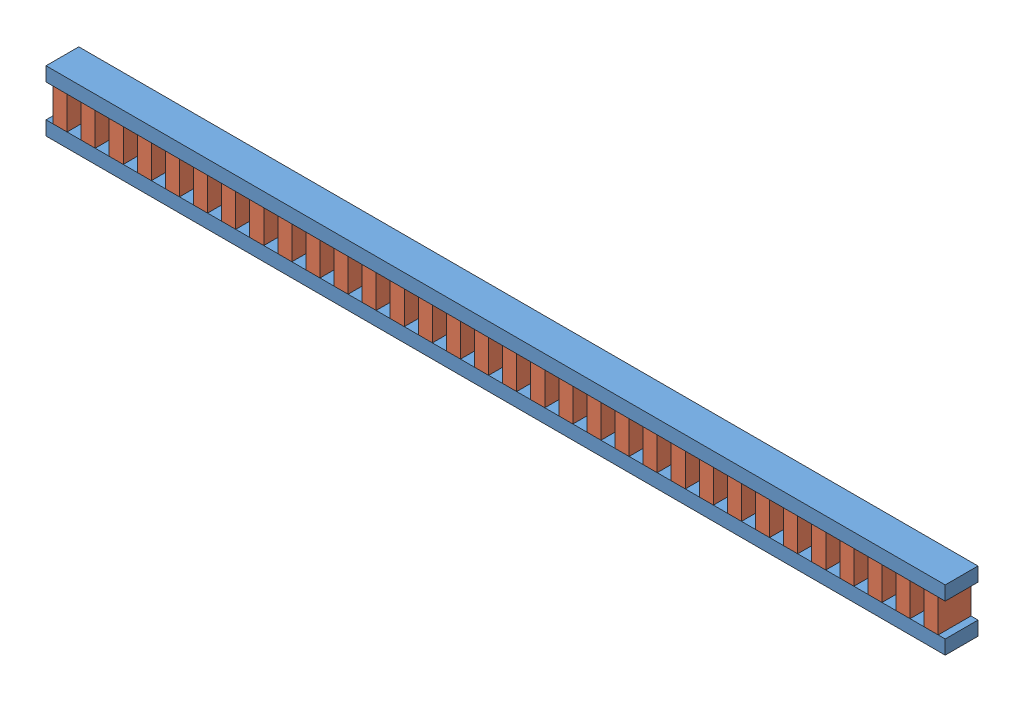
SolidWorks assembly foot_post, configuration Default. Lengths in mm.
Overall size (2438.4 165.1 88.9).
34 component instances, 2 part files, 13 mates.
Components (placement in the parent):
- 2x4_foot-1: 2x4_foot [Default] at (-704.8006 1778.2043 2380.3143) size (2438.4 38.1 88.9)
- 2x4_foot-2: 2x4_foot [Default] at (-704.8006 1689.3043 2469.2143) x (1 0 0) z (0 0 -1) size (2438.4 38.1 88.9)
- 4x4x2_gusset-32: 4x4x2_gusset [Default] at (571.5494 1689.3043 2380.3143) x (0 1 0) z (0 0 1) size (88.9 38.1 88.9)
- 4x4x2_gusset-33: 4x4x2_gusset [Default] at (495.3494 1689.3043 2380.3143) x (0 1 0) z (0 0 1) size (88.9 38.1 88.9)
- 4x4x2_gusset-34: 4x4x2_gusset [Default] at (419.1494 1689.3043 2380.3143) x (0 1 0) z (0 0 1) size (88.9 38.1 88.9)
- 4x4x2_gusset-35: 4x4x2_gusset [Default] at (342.9494 1689.3043 2380.3143) x (0 1 0) z (0 0 1) size (88.9 38.1 88.9)
- 4x4x2_gusset-36: 4x4x2_gusset [Default] at (266.7494 1689.3043 2380.3143) x (0 1 0) z (0 0 1) size (88.9 38.1 88.9)
- 4x4x2_gusset-37: 4x4x2_gusset [Default] at (190.5494 1689.3043 2380.3143) x (0 1 0) z (0 0 1) size (88.9 38.1 88.9)
- 4x4x2_gusset-38: 4x4x2_gusset [Default] at (114.3494 1689.3043 2380.3143) x (0 1 0) z (0 0 1) size (88.9 38.1 88.9)
- 4x4x2_gusset-39: 4x4x2_gusset [Default] at (38.1494 1689.3043 2380.3143) x (0 1 0) z (0 0 1) size (88.9 38.1 88.9)
- 4x4x2_gusset-40: 4x4x2_gusset [Default] at (-38.0506 1689.3043 2380.3143) x (0 1 0) z (0 0 1) size (88.9 38.1 88.9)
- 4x4x2_gusset-41: 4x4x2_gusset [Default] at (-114.2506 1689.3043 2380.3143) x (0 1 0) z (0 0 1) size (88.9 38.1 88.9)
- 4x4x2_gusset-42: 4x4x2_gusset [Default] at (-190.4506 1689.3043 2380.3143) x (0 1 0) z (0 0 1) size (88.9 38.1 88.9)
- 4x4x2_gusset-43: 4x4x2_gusset [Default] at (-266.6506 1689.3043 2380.3143) x (0 1 0) z (0 0 1) size (88.9 38.1 88.9)
- 4x4x2_gusset-44: 4x4x2_gusset [Default] at (-342.8506 1689.3043 2380.3143) x (0 1 0) z (0 0 1) size (88.9 38.1 88.9)
- 4x4x2_gusset-45: 4x4x2_gusset [Default] at (-419.0506 1689.3043 2380.3143) x (0 1 0) z (0 0 1) size (88.9 38.1 88.9)
- 4x4x2_gusset-46: 4x4x2_gusset [Default] at (-495.2506 1689.3043 2380.3143) x (0 1 0) z (0 0 1) size (88.9 38.1 88.9)
- 4x4x2_gusset-47: 4x4x2_gusset [Default] at (-571.4506 1689.3043 2380.3143) x (0 1 0) z (0 0 1) size (88.9 38.1 88.9)
- 4x4x2_gusset-48: 4x4x2_gusset [Default] at (-647.6506 1689.3043 2380.3143) x (0 1 0) z (0 0 1) size (88.9 38.1 88.9)
- 4x4x2_gusset-49: 4x4x2_gusset [Default] at (647.7494 1689.3043 2380.3143) x (0 1 0) z (0 0 1) size (88.9 38.1 88.9)
- 4x4x2_gusset-50: 4x4x2_gusset [Default] at (723.9494 1689.3043 2380.3143) x (0 1 0) z (0 0 1) size (88.9 38.1 88.9)
- 4x4x2_gusset-51: 4x4x2_gusset [Default] at (800.1494 1689.3043 2380.3143) x (0 1 0) z (0 0 1) size (88.9 38.1 88.9)
- 4x4x2_gusset-52: 4x4x2_gusset [Default] at (876.3494 1689.3043 2380.3143) x (0 1 0) z (0 0 1) size (88.9 38.1 88.9)
- 4x4x2_gusset-53: 4x4x2_gusset [Default] at (952.5494 1689.3043 2380.3143) x (0 1 0) z (0 0 1) size (88.9 38.1 88.9)
- 4x4x2_gusset-54: 4x4x2_gusset [Default] at (1028.7494 1689.3043 2380.3143) x (0 1 0) z (0 0 1) size (88.9 38.1 88.9)
- 4x4x2_gusset-55: 4x4x2_gusset [Default] at (1104.9494 1689.3043 2380.3143) x (0 1 0) z (0 0 1) size (88.9 38.1 88.9)
- 4x4x2_gusset-56: 4x4x2_gusset [Default] at (1181.1494 1689.3043 2380.3143) x (0 1 0) z (0 0 1) size (88.9 38.1 88.9)
- 4x4x2_gusset-57: 4x4x2_gusset [Default] at (1257.3494 1689.3043 2380.3143) x (0 1 0) z (0 0 1) size (88.9 38.1 88.9)
- 4x4x2_gusset-58: 4x4x2_gusset [Default] at (1333.5494 1689.3043 2380.3143) x (0 1 0) z (0 0 1) size (88.9 38.1 88.9)
- 4x4x2_gusset-59: 4x4x2_gusset [Default] at (1409.7494 1689.3043 2380.3143) x (0 1 0) z (0 0 1) size (88.9 38.1 88.9)
- 4x4x2_gusset-60: 4x4x2_gusset [Default] at (1485.9494 1689.3043 2380.3143) x (0 1 0) z (0 0 1) size (88.9 38.1 88.9)
- 4x4x2_gusset-61: 4x4x2_gusset [Default] at (1562.1494 1689.3043 2380.3143) x (0 1 0) z (0 0 1) size (88.9 38.1 88.9)
- 4x4x2_gusset-62: 4x4x2_gusset [Default] at (1638.3494 1689.3043 2380.3143) x (0 1 0) z (0 0 1) size (88.9 38.1 88.9)
- 4x4x2_gusset-63: 4x4x2_gusset [Default] at (1714.5494 1689.3043 2380.3143) x (0 1 0) z (0 0 1) size (88.9 38.1 88.9)
Mates (geometry in assembly coordinates):
- Coincident1: coincident: plane of 2x4_foot-1 through (-704.8006 1816.3043 2380.3143) normal (0 0 -1); plane of 2x4_foot-2 through (-704.8006 1651.2043 2380.3143) normal (0 0 -1)
- Coincident2: coincident: plane of 2x4_foot-1 through (-704.8006 1816.3043 2380.3143) normal (-1 0 0); plane of 2x4_foot-2 through (-704.8006 1651.2043 2469.2143) normal (-1 0 0)
- Coincident3: coincident: plane of 2x4_foot-1 through (-704.8006 1778.2043 2380.3143) normal (0 -1 0); plane of ? through (495.3494 1778.2043 2380.3143) normal (0 1 0)
- Coincident4: coincident: line of 2x4_foot-1 through (533.4494 1778.2043 2469.2143) axis (0 0 -1); line of ? through (533.4494 1778.2043 2469.2143) axis (0 0 -1)
- Coincident5: coincident: plane of 2x4_foot-1 through (-704.8006 1816.3043 2380.3143) normal (0 0 -1); plane of ? through (495.3494 1689.3043 2380.3143) normal (0 0 -1)
- Coincident6: coincident: line of 2x4_foot-2 through (533.4494 1689.3043 2380.3143) axis (0 0 1); line of ? through (533.4494 1689.3043 2380.3143) axis (0 0 1)
- Distance1: distance = 38.1 mm: plane of ? through (457.2494 1689.3043 2380.3143) normal (1 0 0); plane of ? through (495.3494 1689.3043 2380.3143) normal (-1 0 0)
- Coincident8: coincident: plane of 2x4_foot-2 through (-704.8006 1689.3043 2469.2143) normal (0 1 0); plane of ? through (419.1494 1689.3043 2380.3143) normal (0 -1 0)
- Coincident9: coincident: plane of 2x4_foot-2 through (-704.8006 1651.2043 2380.3143) normal (0 0 -1); plane of ? through (419.1494 1689.3043 2380.3143) normal (0 0 -1)
- Coincident13: coincident: plane of 2x4_foot-1 through (-704.8006 1778.2043 2380.3143) normal (0 -1 0); plane of 4x4x2_gusset-32 through (533.4494 1778.2043 2380.3143) normal (0 1 0)
- Coincident14: coincident: plane of 2x4_foot-2 through (-704.8006 1689.3043 2469.2143) normal (0 1 0); plane of 4x4x2_gusset-32 through (533.4494 1689.3043 2380.3143) normal (0 -1 0)
- Coincident15: coincident: plane of 2x4_foot-2 through (-704.8006 1651.2043 2380.3143) normal (0 0 -1); plane of 4x4x2_gusset-32 through (533.4494 1689.3043 2380.3143) normal (0 0 -1)
- Coincident17: coincident: point of 2x4_foot-2; point of 4x4x2_gusset-32
